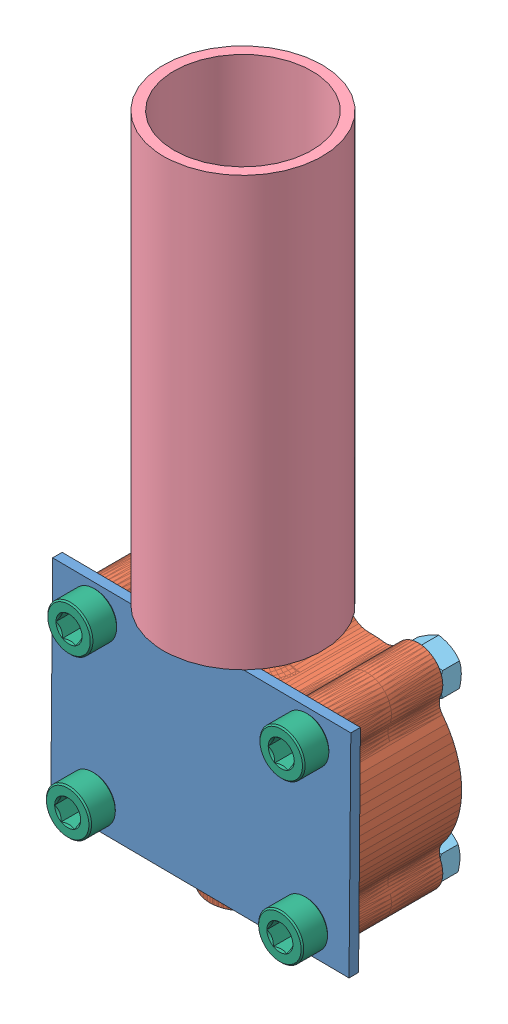
SolidWorks assembly GearAssem, configuration Default. Lengths in mm.
Overall size (79.73 177.87 45.46).
13 component instances, 6 part files, 23 mates.
Components (placement in the parent):
- extruder_cover_piece-1: extruder_cover_piece [Default] at (-23.7615 122.2937 136.0516) x (0.999964 -0.008472 0) z (0 0 1) size (79.25 56.64 2.54)
- gear_again_lol-1: gear_again_lol [Default] at (-63.4758 89.9081 108.7516) size (79.16 64.07 27.3)
- gear_tight_fixed-1: gear_tight_fixed [Default] at (13.6569 112.7005 136.7516) x (-0.923728 -0.383049 0) z (0 0 -1) size (33.84 34.79 20)
- simple_vat-1: simple_vat [Default] at (-23.9371 153.982 127.2225) size (42.16 126.79 42.16)
- gear_tight_fixed-2: gear_tight_fixed [Default] at (-18.2331 133.7895 136.7516) x (-0.185456 -0.982652 0) z (0 0 -1) size (33.84 34.79 20)
- 90592A018_Steel Hex Nut-1: 90592A018_Steel Hex Nut [90592A018] at (-52.1341 101.3243 106.0016) x (1 0 0) z (0 -1 0) size (11 6.28 12.7)
- 91290A162_Black-Oxide Alloy Steel Socket Head Screw-3: 91290A162_Black-Oxide Alloy Steel Socket Head Screw [91290A162] at (4.6112 143.2631 134.0916) size (12 12 23.47)
- 91290A162_Black-Oxide Alloy Steel Socket Head Screw-5: 91290A162_Black-Oxide Alloy Steel Socket Head Screw [91290A162] at (4.2519 100.8466 134.0916) size (12 12 23.47)
- 91290A162_Black-Oxide Alloy Steel Socket Head Screw-6: 91290A162_Black-Oxide Alloy Steel Socket Head Screw [91290A162] at (-51.7748 143.7408 134.0916) size (12 12 23.47)
- 91290A162_Black-Oxide Alloy Steel Socket Head Screw-7: 91290A162_Black-Oxide Alloy Steel Socket Head Screw [91290A162] at (-52.1341 101.3243 134.0916) size (12 12 23.47)
- 90592A018_Steel Hex Nut-2: 90592A018_Steel Hex Nut [90592A018] at (4.2519 100.8466 106.0016) x (1 0 0) z (0 -1 0) size (11 6.28 12.7)
- 90592A018_Steel Hex Nut-3: 90592A018_Steel Hex Nut [90592A018] at (4.6112 143.2631 106.0016) x (1 0 0) z (0 -1 0) size (11 6.28 12.7)
- 90592A018_Steel Hex Nut-4: 90592A018_Steel Hex Nut [90592A018] at (-51.7748 143.7408 106.0016) x (1 0 0) z (0 -1 0) size (11 6.28 12.7)
Mates (geometry in assembly coordinates):
- Coincident1: coincident anti-aligned: plane of extruder_cover_piece-1 through (-23.7615 122.2937 136.0516) normal (0 0 -1); plane of gear_again_lol-1 through (-63.4758 89.9081 136.0516) normal (0 0 1)
- Distance1: distance = 42.8599 mm: line of extruder_cover_piece-1 through (-63.1441 150.9494 138.5916) axis (-0.008472 -0.999964 0); point of gear_again_lol-1
- Coincident3: coincident anti-aligned: plane of gear_again_lol-1 through (-63.4758 89.9081 116.7516) normal (0 0 1); plane of gear_tight_fixed-2 through (-18.2331 133.7895 116.7516) normal (0 0 -1)
- Coincident4: coincident aligned: line of gear_again_lol-1 through (-37.0941 121.982 110.7516) axis (0 0 1); line of gear_tight_fixed-2 through (-37.0941 121.982 116.7516) axis (0 0 1)
- Coincident5: coincident anti-aligned: plane of gear_again_lol-1 through (-63.4758 89.9081 116.7516) normal (0 0 1); plane of gear_tight_fixed-1 through (13.6569 112.7005 116.7516) normal (0 0 -1)
- Coincident6: coincident: moEndPointRef_w of gear_again_lol-1; line of gear_tight_fixed-1 through (-10.6846 121.8316 116.7516) axis (0 0 1)
- Concentric1: concentric anti-aligned: circle of extruder_cover_piece-1; cylinder of 91290A162_Black-Oxide Alloy Steel Socket Head Screw-7 through (-52.1341 101.3243 122.5916) axis (0 0 -1) radius 6
- Coincident7: coincident anti-aligned: plane of extruder_cover_piece-1 through (-23.7615 122.2937 138.5916) normal (0 0 1); plane of 91290A162_Black-Oxide Alloy Steel Socket Head Screw-7 through (-57.7841 101.3243 138.5916) normal (0 0 -1)
- Coincident8: coincident anti-aligned: circle of extruder_cover_piece-1; plane of 91290A162_Black-Oxide Alloy Steel Socket Head Screw-5 through (-1.3981 100.8466 138.5916) normal (0 0 -1)
- Concentric2: concentric anti-aligned: circle of extruder_cover_piece-1; cylinder of 91290A162_Black-Oxide Alloy Steel Socket Head Screw-5 through (4.2519 100.8466 122.5916) axis (0 0 -1) radius 6
- Concentric3: concentric anti-aligned: circle of extruder_cover_piece-1; cylinder of 91290A162_Black-Oxide Alloy Steel Socket Head Screw-6 through (-51.7748 143.7408 122.5916) axis (0 0 -1) radius 6
- Coincident9: coincident: line of extruder_cover_piece-1 through (-63.1441 150.9494 138.5916) axis (-0.008472 -0.999964 0); plane of 91290A162_Black-Oxide Alloy Steel Socket Head Screw-6 through (-57.4248 143.7408 138.5916) normal (0 0 -1)
- Coincident10: coincident anti-aligned: circle of extruder_cover_piece-1; plane of 91290A162_Black-Oxide Alloy Steel Socket Head Screw-3 through (-1.0388 143.2631 138.5916) normal (0 0 -1)
- Concentric4: concentric anti-aligned: circle of extruder_cover_piece-1; cylinder of 91290A162_Black-Oxide Alloy Steel Socket Head Screw-3 through (4.6112 143.2631 122.5916) axis (0 0 -1) radius 6
- Coincident11: coincident anti-aligned: plane of gear_again_lol-1 through (-63.4758 89.9081 108.7516) normal (0 0 -1); plane of 90592A018_Steel Hex Nut-1 through (-57.6341 104.4997 108.7516) normal (0 0 1)
- Concentric6: concentric anti-aligned: cone of 90592A018_Steel Hex Nut-1 through (-52.1341 101.3243 103.2516) axis (0 0 1); cylinder of 91290A162_Black-Oxide Alloy Steel Socket Head Screw-7 through (-52.1341 101.3243 122.5916) axis (0 0 -1) radius 6
- Coincident12: coincident anti-aligned: plane of gear_again_lol-1 through (-63.4758 89.9081 108.7516) normal (0 0 -1); plane of 90592A018_Steel Hex Nut-2 through (-1.2481 104.022 108.7516) normal (0 0 1)
- Concentric7: concentric anti-aligned: circle of 91290A162_Black-Oxide Alloy Steel Socket Head Screw-5; circle of 90592A018_Steel Hex Nut-2
- Coincident14: coincident anti-aligned: plane of gear_again_lol-1 through (-63.4758 89.9081 108.7516) normal (0 0 -1); plane of 90592A018_Steel Hex Nut-4 through (-57.2748 146.9162 108.7516) normal (0 0 1)
- Concentric8: concentric anti-aligned: circle of 91290A162_Black-Oxide Alloy Steel Socket Head Screw-6; circle of 90592A018_Steel Hex Nut-4
- Coincident15: coincident anti-aligned: plane of gear_again_lol-1 through (-63.4758 89.9081 108.7516) normal (0 0 -1); plane of 90592A018_Steel Hex Nut-3 through (-0.8888 146.4385 108.7516) normal (0 0 1)
- Concentric9: concentric anti-aligned: circle of 91290A162_Black-Oxide Alloy Steel Socket Head Screw-3; circle of 90592A018_Steel Hex Nut-3
- Coincident16: coincident anti-aligned: plane of gear_again_lol-1 through (-63.4758 153.982 108.7516) normal (0 1 0); plane of simple_vat-1 through (-23.9371 153.982 127.2225) normal (0 -1 0)
